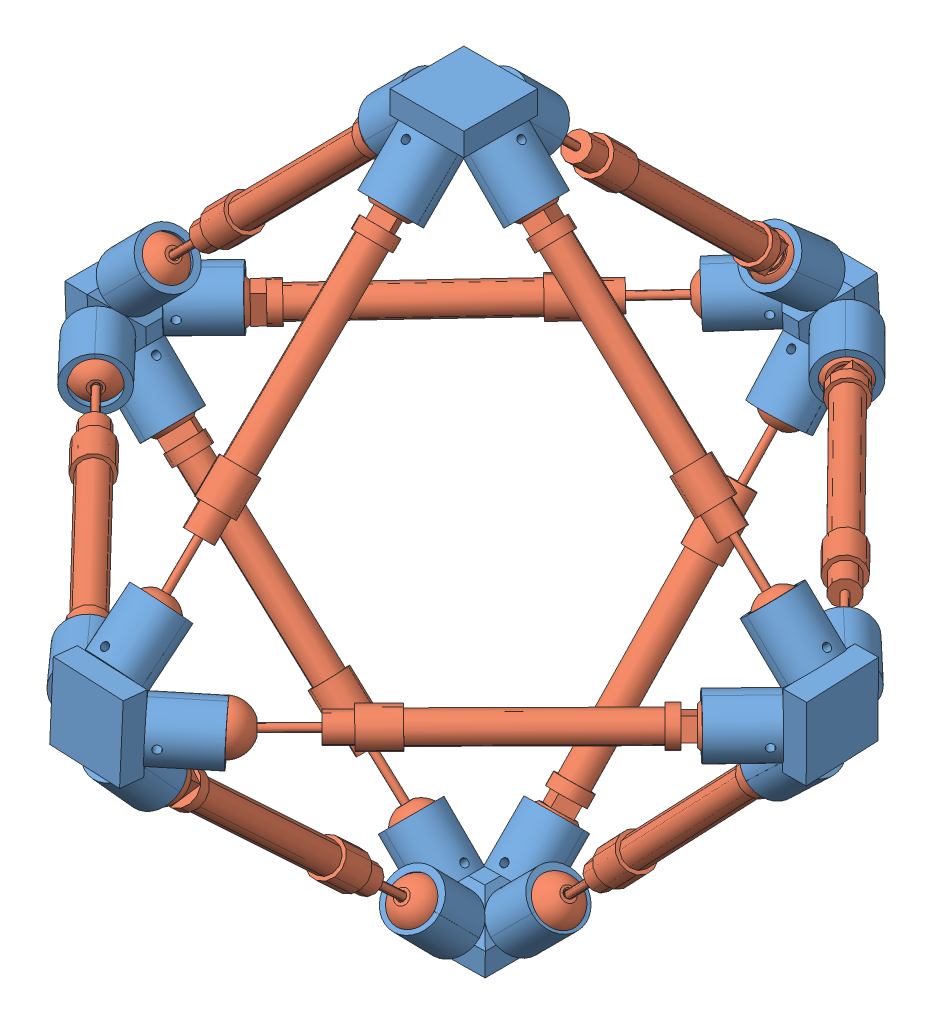
SolidWorks assembly Mecanismo, configuration Predeterminado. Lengths in mm.
Overall size (323.46 322.46 330.84).
18 component instances, 2 part files, 16 mates.
Components (placement in the parent):
- Acople integrado-1: Acople integrado [Predeterminado] at (-96.8409 9.7968 -31.6393) size (79.56 37.79 79.71)
- actuador esferas-1: actuador esferas [Predeterminado] at (-89.7417 -149.5093 264.841) x (0.894158 -0.321589 -0.311547) z (0.008772 0.708252 -0.705905) size (20.02 20.04 171.92)
- Acople integrado-2: Acople integrado [Predeterminado] at (-96.085 -237.2916 222.7411) x (-0.998589 -0.0074 -0.052585) z (-0.004587 0.998562 -0.053418) size (79.56 37.79 79.71)
- actuador esferas-2: actuador esferas [Predeterminado] at (97.6709 -140.5966 76.3324) x (0.57791 0.60778 -0.544633) z (-0.719681 0.694216 0.011053) size (20.02 20.04 171.92)
- actuador esferas-3: actuador esferas [Predeterminado] at (-88.9356 60.5306 101.6621) x (0.987545 -0.105155 0.117037) z (0.010035 -0.700247 -0.71383) size (20.02 20.04 171.92)
- actuador esferas-4: actuador esferas [Predeterminado] at (-274.6065 -156.0651 80.0695) x (0.70366 -0.692169 -0.160513) z (0.702336 0.711782 0.009541) size (20.02 20.04 171.92)
- Acople integrado-3: Acople integrado [Predeterminado] at (-93.2862 -13.9017 -51.5223) x (-0.999972 0.006541 -0.003519) z (-0.006282 -0.997591 -0.069092) size (79.56 37.79 79.71)
- Acople integrado-4: Acople integrado [Predeterminado] at (43.7428 -12.9259 79.9202) x (-0.027903 0.016232 -0.999479) z (-0.023296 -0.999607 -0.015584) size (79.56 37.79 79.71)
- Acople integrado-5: Acople integrado [Predeterminado] at (-234.0687 -129.1628 188.5231) x (0.008635 -0.999581 -0.027629) z (0.027407 0.027856 -0.999236) size (79.56 37.79 79.71)
- Acople integrado-6: Acople integrado [Predeterminado] at (-96.3342 -265.3809 -40.4254) x (-0.999937 -0.001172 0.011174) z (0.011163 0.00892 0.999898) size (79.56 37.79 79.71)
- actuador esferas-5: actuador esferas [Predeterminado] at (-274.4453 -129.6987 48.2973) x (0.718769 0.01827 -0.695009) z (0.695151 -0.002077 0.718861) size (20.02 20.04 171.92)
- actuador esferas-6: actuador esferas [Predeterminado] at (-66.6743 -127.4591 -104.073) x (0.715228 0.024379 0.698466) z (-0.698359 -0.014061 0.715609) size (20.02 20.04 171.92)
- actuador esferas-13: actuador esferas [Predeterminado] at (94.9377 -125.7253 95.6685) x (0.499522 -0.717993 -0.484731) z (-0.701732 -0.007251 -0.712404) size (20.02 20.04 171.92)
- actuador esferas-14: actuador esferas [Predeterminado] at (-112.5078 -130.2343 267.4664) x (0.307321 -0.90217 0.302725) z (0.706408 0.003132 -0.707798) size (20.02 20.04 171.92)
- actuador esferas-15: actuador esferas [Predeterminado] at (-92.5221 -105.5256 -114.7018) x (0.648452 -0.523074 -0.553086) z (-0.007878 -0.731117 0.682207) size (20.02 20.04 171.92)
- actuador esferas-16: actuador esferas [Predeterminado] at (-99.2419 -305.6532 43.0828) x (-0.874389 0.349321 -0.336776) z (-0.009208 0.681991 0.731303) size (20.02 20.04 171.92)
- actuador esferas-17: actuador esferas [Predeterminado] at (-74.7386 -314.5693 60.7473) x (-0.513379 -0.469942 -0.71805) z (-0.701313 0.711972 0.035449) size (20.02 20.04 171.92)
- actuador esferas-18: actuador esferas [Predeterminado] at (-114.9572 -312.2832 59.7352) x (-0.324992 0.360152 -0.874454) z (0.691173 0.721564 0.040307) size (20.02 20.04 171.92)
Mates (geometry in assembly coordinates):
- Concéntrica1: concentric: sphere of Acople integrado-1; sphere of actuador esferas-1
- Concéntrica2: concentric: sphere of actuador esferas-1; sphere of Acople integrado-2
- Concéntrica3: concentric: sphere of Acople integrado-1; sphere of actuador esferas-2
- Concéntrica4: concentric: sphere of Acople integrado-1; sphere of actuador esferas-3
- Concéntrica5: concentric: sphere of Acople integrado-1; sphere of actuador esferas-4
- Concéntrica6: concentric: sphere of actuador esferas-3; sphere of Acople integrado-3
- Concéntrica7: concentric: sphere of actuador esferas-2; sphere of Acople integrado-4
- Concéntrica8: concentric: sphere of actuador esferas-4; sphere of Acople integrado-5
- Concéntrica9: concentric: sphere of Acople integrado-2; sphere of actuador esferas-5
- Concéntrica13: concentric: sphere of Acople integrado-3; sphere of actuador esferas-6
- Concéntrica16: concentric: sphere of Acople integrado-4; sphere of actuador esferas-13
- Concéntrica17: concentric: sphere of Acople integrado-4; sphere of actuador esferas-14
- Concéntrica18: concentric: sphere of Acople integrado-3; sphere of actuador esferas-15
- Concéntrica19: concentric: sphere of Acople integrado-6; sphere of actuador esferas-15
- Concéntrica24: concentric: sphere of Acople integrado-5; sphere of actuador esferas-17
- Concéntrica25: concentric: sphere of Acople integrado-4; sphere of actuador esferas-18
